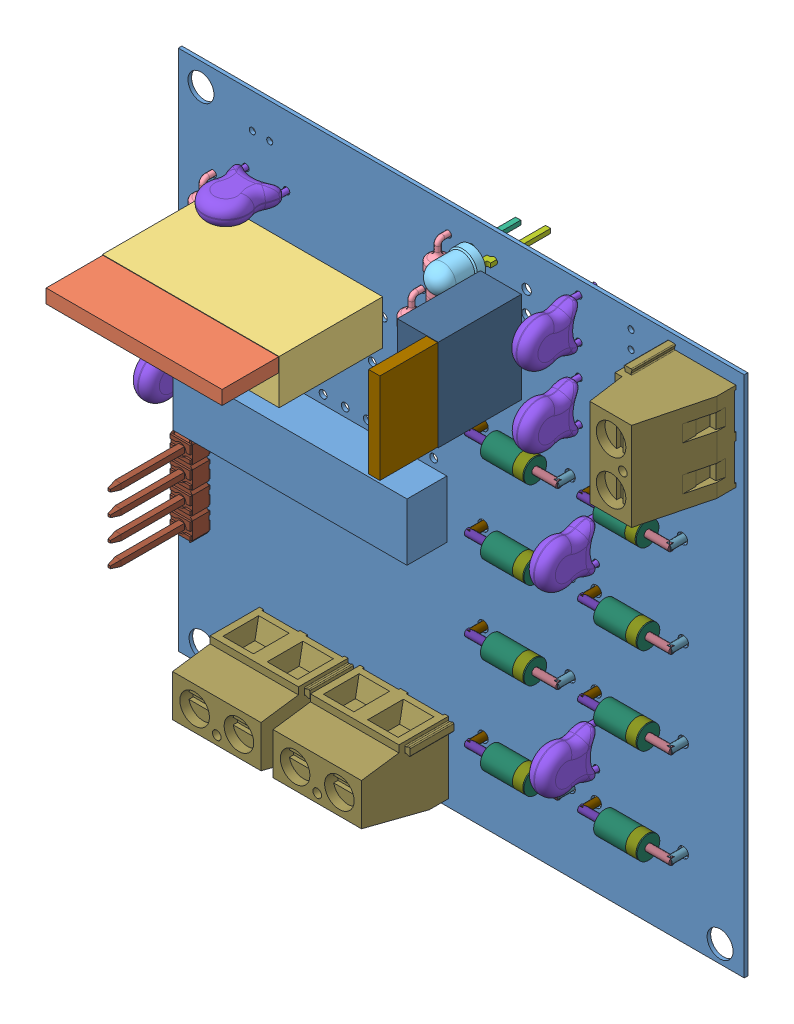
SolidWorks assembly l298, configuration Default. Lengths in mm.
Overall size (65 60 27.2).
151 component instances, 19 part files, 0 mates.
Components (placement in the parent):
- Board-1: Board [Default] at origin size (65 60 0.41)
  - Open CASCADE STEP translator 6.8 1.1.1-1: Open CASCADE STEP translator 6.8 1.1.1 [Default] at (0 0 -0.4115) size (65 60 0.41)
- U2-1: U2 [Default] at origin size (20.3 5.1 18.4)
  - -1733505456-1: -1733505456 [Default] at (471.92 301.75 14.49) size (20.2 1.6 6.51)
    - Extruded-1: Extruded [Default] at origin size (20.2 1.6 6.51)
  - -1733503536-1: -1733503536 [Default] at (471.92 300.05 2.6) size (20.3 5.1 11.89)
    - Extruded_2-1: Extruded_2 [Default] at origin size (20.3 5.1 11.89)
- R3-1: R3 [Default] at origin size (2.4 10.76 4.41)
  - User_Library-Res40-Axial_Short_0_25W-5_6K-1: User_Library-Res40-Axial_Short_0_25W-5_6K [Default] at (484.0001 297.9999 0) x (0 -1 0) z (0 0 1) size (10.76 2.4 4.41)
- R2-1: R2 [Default] at origin size (2.4 10.76 4.41)
  - User_Library-Res40-Axial_Short_0_25W-5_6K-1: User_Library-Res40-Axial_Short_0_25W-5_6K [Default] at (459.9999 297.5001 0) x (0 1 0) z (0 0 1) size (10.76 2.4 4.41)
- R1-1: R1 [Default] at origin size (2.4 10.76 4.41)
  - User_Library-Res40-Axial_Short_0_25W-5_6K-1: User_Library-Res40-Axial_Short_0_25W-5_6K [Default] at (487.0001 304.9999 0) x (0 -1 0) z (0 0 1) size (10.76 2.4 4.41)
- D9-1: D9 [Default] at origin size (3.4 3.4 12.4)
  - User_Library-LA_3366_sc-1: User_Library-LA_3366_sc [Default] at (491.0001 310.0001 1.397) size (3.4 3.4 12.4)
    - User_Library-LA_3366_sc_BODY_amber-1: User_Library-LA_3366_sc_BODY_amber [Default] x (1 0 0) z (0 -1 0) size (3.4 4.8 3.4)
    - User_Library-LA_3366_sc_LEAD_A_sc-1: User_Library-LA_3366_sc_LEAD_A_sc [Default] at (0 0.25 0) x (1 0 0) z (0 -1 0) size (1.12 6.7 0.5)
    - User_Library-LA_3366_sc_LEAD_K_sc-1: User_Library-LA_3366_sc_LEAD_K_sc [Default] at (0 -0.25 0) x (-1 0 0) z (0 1 0) size (1.12 7.6 0.5)
- C4-1: C4 [Default] at origin size (2.51 5.57 9)
  - User_Library-CAP-CER-DISC5-1: User_Library-CAP-CER-DISC5 [Default] at (500.7249 309.0845 4.6263) x (0 1 0) z (0 0 -1) size (5.57 2.51 9)
- U1-1: U1 [Default] at origin size (4.7 10.5 16.2)
  - -1733502736-1: -1733502736 [Default] at (498.2 306.46 13.05) size (1.3 10.4 6.65)
    - Extruded_3-1: Extruded_3 [Default] at origin size (1.3 10.4 6.65)
  - -1733506176-1: -1733506176 [Default] at (496.55 306.46 3.5) size (4.7 10.5 9.55)
    - Extruded_4-1: Extruded_4 [Default] at origin size (4.7 10.5 9.55)
- STM-1: STM [Default] at origin size (2.49 10.16 13.46)
  - 022284041-1: 022284041 [Default] at (458.4998 271.6898 1.1706) x (0 1 0) z (1 0 0) size (10.16 13.46 2.49)
    - Open CASCADE STEP translator 6.8 1.9.1.1-1: Open CASCADE STEP translator 6.8 1.9.1.1 [Default] at origin size (10.16 13.46 2.49)
- source-1: source [Default] at origin size (8.2 10.76 13.5)
  - 282837-2_2-Pos-Vert_200mil-1: 282837-2_2-Pos-Vert_200mil [Default] at (511.8999 306.4601 2.794) x (0 -1 0) z (-1 0 0) size (10.76 13.5 8.2)
- M2-1: M2 [Default] at origin size (10.76 8.2 13.5)
  - 282837-2_2-Pos-Vert_200mil-1: 282837-2_2-Pos-Vert_200mil [Default] at (470.4601 262.1001 2.794) x (-1 0 0) z (0 1 0) size (10.76 13.5 8.2)
- M1-1: M1 [Default] at origin size (10.76 8.2 13.5)
  - 282837-2_2-Pos-Vert_200mil-1: 282837-2_2-Pos-Vert_200mil [Default] at (482.0001 262.1001 2.794) x (-1 0 0) z (0 1 0) size (10.76 13.5 8.2)
- D8-1: D8 [Default] at origin size (10.8 2.61 3.81)
  - -1733042672-1: -1733042672 [Default] at (501.2503 282.9977 1.5) x (0 0 -1) z (-1 0 0) size (0.8 0.8 2.75)
    - Cylinder-1: Cylinder [Default] at origin size (0.8 0.8 2.75)
  - -1733042992-1: -1733042992 [Default] at (500.9999 282.9999 -1) x (-1 0 0) z (0 0 1) size (0.8 0.8 2.69)
    - Cylinder_2-1: Cylinder_2 [Default] at origin size (0.8 0.8 2.69)
  - -1733042432-1: -1733042432 [Default] at (498.5001 282.9975 1.5) x (0 0 -1) z (-1 0 0) size (2.6 2.6 5)
    - Cylinder_3-1: Cylinder_3 [Default] at origin size (2.6 2.6 5)
  - -1733042152-1: -1733042152 [Default] at (498.3731 282.9976 1.5) x (0 0 -1) z (-1 0 0) size (2.61 2.61 1.2)
    - Cylinder_4-1: Cylinder_4 [Default] at origin size (2.61 2.61 1.2)
  - -1733041072-1: -1733041072 [Default] at (490.7497 283.0023 1.5) x (0 0 -1) z (1 0 0) size (0.8 0.8 2.75)
    - Cylinder_5-1: Cylinder_5 [Default] at origin size (0.8 0.8 2.75)
  - -1733041192-1: -1733041192 [Default] at (491.0001 283.0001 -1) x (1 0 0) z (0 0 1) size (0.8 0.8 2.69)
    - Cylinder_6-1: Cylinder_6 [Default] at origin size (0.8 0.8 2.69)
- D7-1: D7 [Default] at origin size (10.8 2.61 3.81)
  - -1733042672-1: -1733042672 [Default] at (501.2503 292.9977 1.5) x (0 0 -1) z (-1 0 0) size (0.8 0.8 2.75)
    - Cylinder-1: Cylinder [Default] at origin size (0.8 0.8 2.75)
  - -1733042992-1: -1733042992 [Default] at (500.9999 292.9999 -1) x (-1 0 0) z (0 0 1) size (0.8 0.8 2.69)
    - Cylinder_2-1: Cylinder_2 [Default] at origin size (0.8 0.8 2.69)
  - -1733042432-1: -1733042432 [Default] at (498.5001 292.9975 1.5) x (0 0 -1) z (-1 0 0) size (2.6 2.6 5)
    - Cylinder_3-1: Cylinder_3 [Default] at origin size (2.6 2.6 5)
  - -1733042152-1: -1733042152 [Default] at (498.3731 292.9976 1.5) x (0 0 -1) z (-1 0 0) size (2.61 2.61 1.2)
    - Cylinder_4-1: Cylinder_4 [Default] at origin size (2.61 2.61 1.2)
  - -1733041072-1: -1733041072 [Default] at (490.7497 293.0023 1.5) x (0 0 -1) z (1 0 0) size (0.8 0.8 2.75)
    - Cylinder_5-1: Cylinder_5 [Default] at origin size (0.8 0.8 2.75)
  - -1733041192-1: -1733041192 [Default] at (491.0001 293.0001 -1) x (1 0 0) z (0 0 1) size (0.8 0.8 2.69)
    - Cylinder_6-1: Cylinder_6 [Default] at origin size (0.8 0.8 2.69)
- D6-1: D6 [Default] at origin size (10.8 2.61 3.81)
  - -1733042672-1: -1733042672 [Default] at (514.2502 282.9977 1.5) x (0 0 -1) z (-1 0 0) size (0.8 0.8 2.75)
    - Cylinder-1: Cylinder [Default] at origin size (0.8 0.8 2.75)
  - -1733042992-1: -1733042992 [Default] at (513.9999 282.9999 -1) x (-1 0 0) z (0 0 1) size (0.8 0.8 2.69)
    - Cylinder_2-1: Cylinder_2 [Default] at origin size (0.8 0.8 2.69)
  - -1733042432-1: -1733042432 [Default] at (511.5001 282.9975 1.5) x (0 0 -1) z (-1 0 0) size (2.6 2.6 5)
    - Cylinder_3-1: Cylinder_3 [Default] at origin size (2.6 2.6 5)
  - -1733042152-1: -1733042152 [Default] at (511.3731 282.9976 1.5) x (0 0 -1) z (-1 0 0) size (2.61 2.61 1.2)
    - Cylinder_4-1: Cylinder_4 [Default] at origin size (2.61 2.61 1.2)
  - -1733041072-1: -1733041072 [Default] at (503.7497 283.0023 1.5) x (0 0 -1) z (1 0 0) size (0.8 0.8 2.75)
    - Cylinder_5-1: Cylinder_5 [Default] at origin size (0.8 0.8 2.75)
  - -1733041192-1: -1733041192 [Default] at (504.0001 283.0001 -1) x (1 0 0) z (0 0 1) size (0.8 0.8 2.69)
    - Cylinder_6-1: Cylinder_6 [Default] at origin size (0.8 0.8 2.69)
- D5-1: D5 [Default] at origin size (10.8 2.61 3.81)
  - -1733042672-1: -1733042672 [Default] at (501.2503 261.9977 1.5) x (0 0 -1) z (-1 0 0) size (0.8 0.8 2.75)
    - Cylinder-1: Cylinder [Default] at origin size (0.8 0.8 2.75)
  - -1733042992-1: -1733042992 [Default] at (500.9999 261.9999 -1) x (-1 0 0) z (0 0 1) size (0.8 0.8 2.69)
    - Cylinder_2-1: Cylinder_2 [Default] at origin size (0.8 0.8 2.69)
  - -1733042432-1: -1733042432 [Default] at (498.5001 261.9975 1.5) x (0 0 -1) z (-1 0 0) size (2.6 2.6 5)
    - Cylinder_3-1: Cylinder_3 [Default] at origin size (2.6 2.6 5)
  - -1733042152-1: -1733042152 [Default] at (498.3731 261.9976 1.5) x (0 0 -1) z (-1 0 0) size (2.61 2.61 1.2)
    - Cylinder_4-1: Cylinder_4 [Default] at origin size (2.61 2.61 1.2)
  - -1733041072-1: -1733041072 [Default] at (490.7497 262.0023 1.5) x (0 0 -1) z (1 0 0) size (0.8 0.8 2.75)
    - Cylinder_5-1: Cylinder_5 [Default] at origin size (0.8 0.8 2.75)
  - -1733041192-1: -1733041192 [Default] at (491.0001 262.0001 -1) x (1 0 0) z (0 0 1) size (0.8 0.8 2.69)
    - Cylinder_6-1: Cylinder_6 [Default] at origin size (0.8 0.8 2.69)
- D4-1: D4 [Default] at origin size (10.8 2.61 3.81)
  - -1733042672-1: -1733042672 [Default] at (501.2503 272.9977 1.5) x (0 0 -1) z (-1 0 0) size (0.8 0.8 2.75)
    - Cylinder-1: Cylinder [Default] at origin size (0.8 0.8 2.75)
  - -1733042992-1: -1733042992 [Default] at (500.9999 272.9999 -1) x (-1 0 0) z (0 0 1) size (0.8 0.8 2.69)
    - Cylinder_2-1: Cylinder_2 [Default] at origin size (0.8 0.8 2.69)
  - -1733042432-1: -1733042432 [Default] at (498.5001 272.9975 1.5) x (0 0 -1) z (-1 0 0) size (2.6 2.6 5)
    - Cylinder_3-1: Cylinder_3 [Default] at origin size (2.6 2.6 5)
  - -1733042152-1: -1733042152 [Default] at (498.3731 272.9976 1.5) x (0 0 -1) z (-1 0 0) size (2.61 2.61 1.2)
    - Cylinder_4-1: Cylinder_4 [Default] at origin size (2.61 2.61 1.2)
  - -1733041072-1: -1733041072 [Default] at (490.7497 273.0023 1.5) x (0 0 -1) z (1 0 0) size (0.8 0.8 2.75)
    - Cylinder_5-1: Cylinder_5 [Default] at origin size (0.8 0.8 2.75)
  - -1733041192-1: -1733041192 [Default] at (491.0001 273.0001 -1) x (1 0 0) z (0 0 1) size (0.8 0.8 2.69)
    - Cylinder_6-1: Cylinder_6 [Default] at origin size (0.8 0.8 2.69)
- D3-1: D3 [Default] at origin size (10.8 2.61 3.81)
  - -1733042672-1: -1733042672 [Default] at (514.2502 272.9977 1.5) x (0 0 -1) z (-1 0 0) size (0.8 0.8 2.75)
    - Cylinder-1: Cylinder [Default] at origin size (0.8 0.8 2.75)
  - -1733042992-1: -1733042992 [Default] at (513.9999 272.9999 -1) x (-1 0 0) z (0 0 1) size (0.8 0.8 2.69)
    - Cylinder_2-1: Cylinder_2 [Default] at origin size (0.8 0.8 2.69)
  - -1733042432-1: -1733042432 [Default] at (511.5001 272.9975 1.5) x (0 0 -1) z (-1 0 0) size (2.6 2.6 5)
    - Cylinder_3-1: Cylinder_3 [Default] at origin size (2.6 2.6 5)
  - -1733042152-1: -1733042152 [Default] at (511.3731 272.9976 1.5) x (0 0 -1) z (-1 0 0) size (2.61 2.61 1.2)
    - Cylinder_4-1: Cylinder_4 [Default] at origin size (2.61 2.61 1.2)
  - -1733041072-1: -1733041072 [Default] at (503.7497 273.0023 1.5) x (0 0 -1) z (1 0 0) size (0.8 0.8 2.75)
    - Cylinder_5-1: Cylinder_5 [Default] at origin size (0.8 0.8 2.75)
  - -1733041192-1: -1733041192 [Default] at (504.0001 273.0001 -1) x (1 0 0) z (0 0 1) size (0.8 0.8 2.69)
    - Cylinder_6-1: Cylinder_6 [Default] at origin size (0.8 0.8 2.69)
- D2-1: D2 [Default] at origin size (10.8 2.61 3.81)
  - -1733042672-1: -1733042672 [Default] at (514.2502 261.9977 1.5) x (0 0 -1) z (-1 0 0) size (0.8 0.8 2.75)
    - Cylinder-1: Cylinder [Default] at origin size (0.8 0.8 2.75)
  - -1733042992-1: -1733042992 [Default] at (513.9999 261.9999 -1) x (-1 0 0) z (0 0 1) size (0.8 0.8 2.69)
    - Cylinder_2-1: Cylinder_2 [Default] at origin size (0.8 0.8 2.69)
  - -1733042432-1: -1733042432 [Default] at (511.5001 261.9975 1.5) x (0 0 -1) z (-1 0 0) size (2.6 2.6 5)
    - Cylinder_3-1: Cylinder_3 [Default] at origin size (2.6 2.6 5)
  - -1733042152-1: -1733042152 [Default] at (511.3731 261.9976 1.5) x (0 0 -1) z (-1 0 0) size (2.61 2.61 1.2)
    - Cylinder_4-1: Cylinder_4 [Default] at origin size (2.61 2.61 1.2)
  - -1733041072-1: -1733041072 [Default] at (503.7497 262.0023 1.5) x (0 0 -1) z (1 0 0) size (0.8 0.8 2.75)
    - Cylinder_5-1: Cylinder_5 [Default] at origin size (0.8 0.8 2.75)
  - -1733041192-1: -1733041192 [Default] at (504.0001 262.0001 -1) x (1 0 0) z (0 0 1) size (0.8 0.8 2.69)
    - Cylinder_6-1: Cylinder_6 [Default] at origin size (0.8 0.8 2.69)
- D1-1: D1 [Default] at origin size (10.8 2.61 3.81)
  - -1733042672-1: -1733042672 [Default] at (514.1494 293.1651 1.5) x (0 0 -1) z (-1 0 0) size (0.8 0.8 2.75)
    - Cylinder-1: Cylinder [Default] at origin size (0.8 0.8 2.75)
  - -1733042992-1: -1733042992 [Default] at (513.8991 293.1673 -1) x (-1 0 0) z (0 0 1) size (0.8 0.8 2.69)
    - Cylinder_2-1: Cylinder_2 [Default] at origin size (0.8 0.8 2.69)
  - -1733042432-1: -1733042432 [Default] at (511.3992 293.1649 1.5) x (0 0 -1) z (-1 0 0) size (2.6 2.6 5)
    - Cylinder_3-1: Cylinder_3 [Default] at origin size (2.6 2.6 5)
  - -1733042152-1: -1733042152 [Default] at (511.2722 293.1649 1.5) x (0 0 -1) z (-1 0 0) size (2.61 2.61 1.2)
    - Cylinder_4-1: Cylinder_4 [Default] at origin size (2.61 2.61 1.2)
  - -1733041072-1: -1733041072 [Default] at (503.6489 293.1697 1.5) x (0 0 -1) z (1 0 0) size (0.8 0.8 2.75)
    - Cylinder_5-1: Cylinder_5 [Default] at origin size (0.8 0.8 2.75)
  - -1733041192-1: -1733041192 [Default] at (503.8992 293.1675 -1) x (1 0 0) z (0 0 1) size (0.8 0.8 2.69)
    - Cylinder_6-1: Cylinder_6 [Default] at origin size (0.8 0.8 2.69)
- C9-1: C9 [Default] at origin size (2.51 5.57 9)
  - User_Library-CAP-CER-DISC5-1: User_Library-CAP-CER-DISC5 [Default] at (502.7249 288.0845 4.6263) x (0 1 0) z (0 0 -1) size (5.57 2.51 9)
- C8-1: C8 [Default] at origin size (2.51 5.57 9)
  - User_Library-CAP-CER-DISC5-1: User_Library-CAP-CER-DISC5 [Default] at (502.7499 267.6595 4.6263) x (0 1 0) z (0 0 -1) size (5.57 2.51 9)
- C7-1: C7 [Default] at origin size (5.57 2.51 9)
  - User_Library-CAP-CER-DISC5-1: User_Library-CAP-CER-DISC5 [Default] at (466.0845 306.2751 4.6263) x (1 0 0) z (0 0 -1) size (5.57 2.51 9)
- C6-1: C6 [Default] at origin size (2.51 5.57 9)
  - User_Library-CAP-CER-DISC5-1: User_Library-CAP-CER-DISC5 [Default] at (457.2499 284.1595 4.6263) x (0 1 0) z (0 0 -1) size (5.57 2.51 9)
- C3-1: C3 [Default] at origin size (2.51 5.57 9)
  - User_Library-CAP-CER-DISC5-1: User_Library-CAP-CER-DISC5 [Default] at (503.2751 300.9155 4.6263) x (0 -1 0) z (0 0 -1) size (5.57 2.51 9)
- Imported-1: Imported [Default] at origin size (26.9 6.6 4.57)
  - -1733503016-1: -1733503016 [Default] at (473.897 283.063 0.51) size (26.9 6.6 4.57)
    - Extruded_5-1: Extruded_5 [Default] at origin size (26.9 6.6 4.57)
